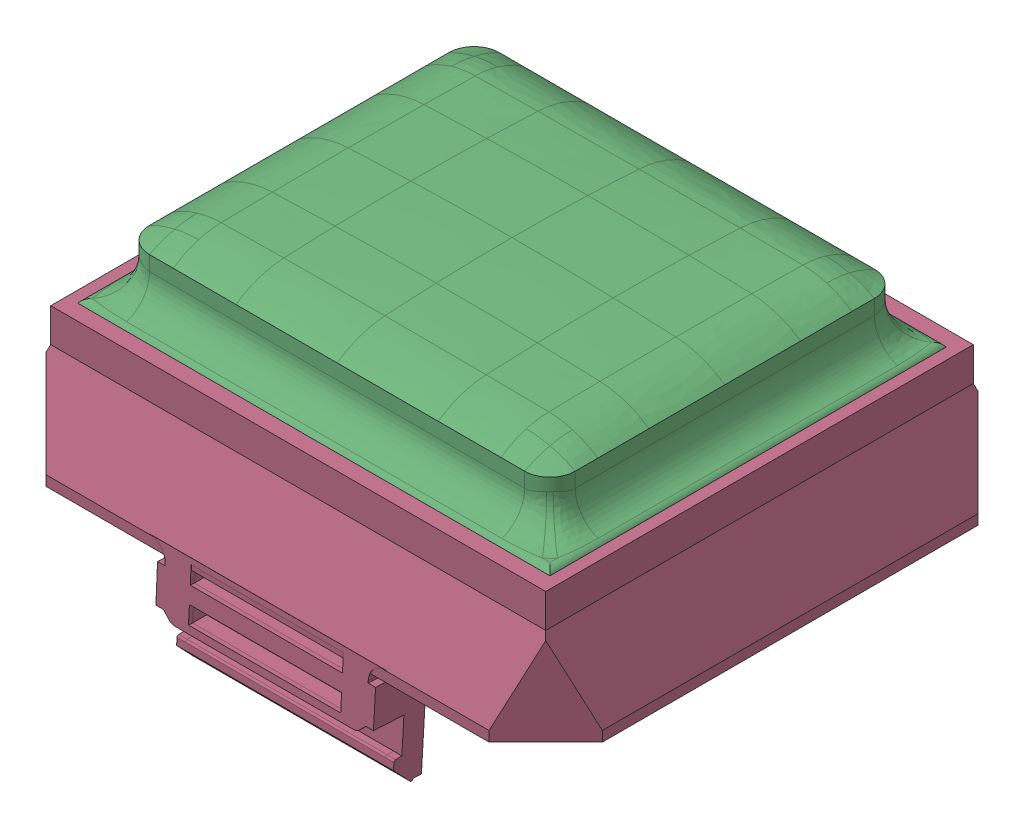
SolidWorks assembly pinmarker_1mm, configuration 默认. Lengths in mm.
Overall size (33 17.51 29.5).
6 component instances, 6 part files, 16 mates.
Components (placement in the parent):
- Lens-1: Lens [默认] at origin size (28.33 2.18 23.83)
- InsideSkin-1: InsideSkin [默认] at (0.0001 0 0.2499) size (23.8 5.49 19.29)
- Topskin-1: Topskin [默认] at (0.0001 2 0.2499) size (28.02 6.25 23.52) (hidden)
- Supportbase-2: Supportbase [默认] at origin size (33 14.02 29.5)
- markerTopTip-1: markerTopTip [默认] at (-10.0749 22.5 -7.8251) x (1 0 0) z (0 -1 0) size (21.2 16.2 0.4)
- Pinmarker1mm_1-1: Pinmarker1mm_1 [默认] at (0.0001 0 0.2499) size (21.57 1.99 16.56)
Mates (geometry in assembly coordinates):
- 同心2: concentric anti-aligned: cylinder of NewInsideSkin_conti-1 through (10.8751 17.7531 8.6249) axis (0 1 0) radius 0.7; cylinder of Board3Con1612611OriginalSkin_TOP-1 through (10.8751 24 8.6249) axis (0 -1 0) radius 0.7
- 同心3: concentric anti-aligned: cylinder of NewInsideSkin_conti-1 through (10.8751 17.7531 -9.1251) axis (0 1 0) radius 0.7; cylinder of Board3Con1612611OriginalSkin_TOP-1 through (10.8751 24 -9.1251) axis (0 -1 0) radius 0.7
- 重合4: coincident aligned: plane of NewInsideSkin_conti-1 through (10.8751 19 -9.1251) normal (0 -1 0); plane of Board3Con1612611OriginalSkin_TOP-1 through (0.0001 19 0.2499) normal (0 -1 0)
- 重合6: coordinate: point of NewContiSupportBase-2
- 重合7: coincident anti-aligned: plane of lensall-1 through (13.75 19 -11.5) normal (0.939693 0.34202 0); plane of NewContiSupportBase-2 through (13.75 19 12.7803) normal (-0.939693 -0.34202 0)
- 同心5: concentric aligned: cylinder of lensall-1 through (13.3294 18.6938 -11.0794) axis (-0.323616 0.889126 0.323616) radius 0.5; cylinder of NewContiSupportBase-2 through (10.7866 25.6801 -8.5366) axis (-0.323616 0.889126 0.323616) radius 0.5
- 重合8: coincident anti-aligned: plane of lensall-1 through (0 18 0) normal (0 -1 0); plane of NewContiSupportBase-2 through (0 18 0) normal (0 1 0)
- 重合9: coincident anti-aligned: plane of lensall-1 through (0 19 0) normal (0 1 0); plane of Board3Con1612611OriginalSkin_TOP-1 through (0.0001 19 0.2499) normal (0 -1 0)
- 重合10: coincident anti-aligned: plane of Board3Con1612611OriginalSkin_TOP-1 through (0.0001 19 11.7499) normal (0 0 1); plane of NewContiSupportBase-2 through (-13.5999 21 11.7499) normal (0 0 -1)
- 重合11: coincident anti-aligned: plane of Board3Con1612611OriginalSkin_TOP-1 through (14.0001 19 0.2499) normal (1 0 0); plane of NewContiSupportBase-2 through (14.0001 21 11.7499) normal (-1 0 0)
- 同心6: concentric aligned: cylinder of InsideSkin-1 through (-10.0749 22.1 7.1749) axis (0 1 0) radius 0.6; cylinder of markerTopTip-1 through (-10.0749 22.1 7.1749) axis (0 1 0) radius 0.6
- 重合12: coincident anti-aligned: plane of InsideSkin-1 through (-10.0749 22.1 7.1749) normal (0 1 0); plane of markerTopTip-1 through (-10.0749 22.1 7.1749) normal (0 -1 0)
- 同心7: concentric aligned: cylinder of InsideSkin-1 through (-10.0749 22.1 4.6749) axis (0 1 0) radius 0.6; cylinder of markerTopTip-1 through (-10.0749 22.1 4.6749) axis (0 1 0) radius 0.6
- 同心8: concentric: cone of InsideSkin-1 through (-10.0749 22.5 7.1749) axis (0 -1 0); cone of Pinmarker1mm_1-1 through (-10.0749 29.0261 7.1749) axis (0 -1 0)
- 同心9: concentric: cone of InsideSkin-1 through (-10.0749 22.5 4.6749) axis (0 -1 0); cone of Pinmarker1mm_1-1 through (-10.0749 29.0261 4.6749) axis (0 -1 0)
- 重合13: coincident anti-aligned: plane of markerTopTip-1 through (-10.0749 22.5 4.6749) normal (0 1 0); plane of Pinmarker1mm_1-1 through (-10.0749 29.0261 4.6749) normal (0 -1 0)
